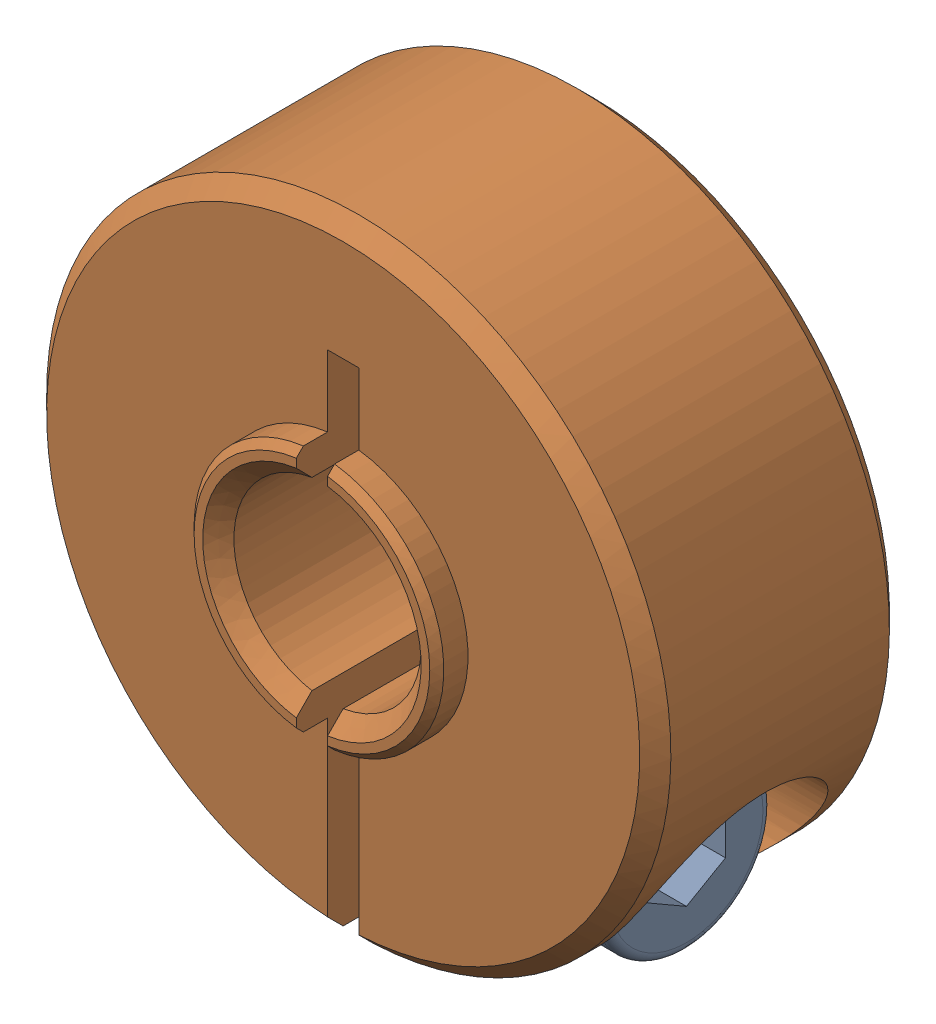
SolidWorks assembly PSCSBN6-8, configuration Default. Lengths in mm.
Overall size (20 19.99 9.01).
2 component instances, 2 part files, 0 mates.
Components (placement in the parent):
- Slotted head cap screw ISO 4762 - M3x10-1: Slotted head cap screw ISO 4762 - M3x10 [Default] at (4 -6 0) x (-1 0 0) z (0 0 1) size (13 5.5 5.5)
- PSCSBN6-8_1-1: PSCSBN6-8_1 [Default] at origin size (20 19.99 9.01)
